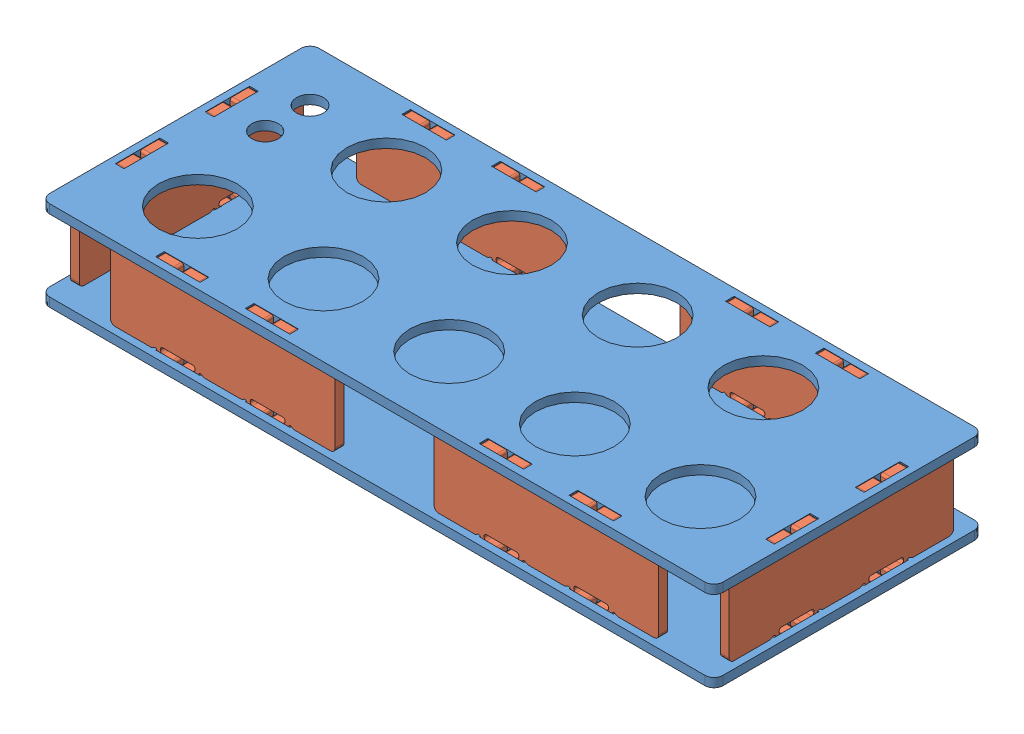
SolidWorks assembly Popn Controller v2, configuration Default. Lengths in mm.
Overall size (750 100 300).
8 component instances, 2 part files, 21 mates.
Components (placement in the parent):
- Face-1: Face [Top] at (-159.3551 406.3492 746.0654) size (750 10 300)
- Support-1: Support [Default] at (-141.3551 326.3492 471.0654) x (0 0 1) z (-1 0 0) size (250 99 10)
- Support-2: Support [Default] at (-89.6051 326.3492 728.0654) size (250 99 10)
- Support-3: Support [Default] at (-89.6051 326.3492 454.0654) size (250 99 10)
- Support-4: Support [Default] at (270.8949 326.3492 454.0654) size (250 99 10)
- Support-5: Support [Default] at (572.6449 406.3492 471.0654) x (0 0 1) z (1 0 0) size (250 99 10)
- Support-6: Support [Default] at (270.8949 326.3492 728.0654) size (250 99 10)
- Face-2: Face [Bottom] at (-159.3551 316.3492 746.0654) size (750 10 300)
Mates (geometry in assembly coordinates):
- Coincident1: coincident anti-aligned: plane of Face-1 through (-159.3551 406.3492 746.0654) normal (0 -1 0); plane of Support-6 through (270.8949 406.3492 738.0654) normal (0 1 0)
- Coincident2: coincident anti-aligned: plane of Face-1 through (370.6449 406.3492 738.0654) normal (0 0 -1); plane of Support-6 through (270.8949 326.3492 738.0654) normal (0 0 1)
- Width1: width anti-aligned: plane of Face-1 through (321.1449 406.3492 738.0654) normal (1 0 0); plane of Face-1 through (470.6449 406.3492 728.4654) normal (-1 0 0); plane of Support-6 through (270.8949 326.3492 738.0654) normal (-1 0 0); plane of Support-6 through (520.8949 326.3492 738.0654) normal (1 0 0)
- Coincident5: coincident anti-aligned: plane of Face-1 through (60.6449 406.3492 738.0654) normal (0 0 -1); plane of Support-2 through (-89.6051 326.3492 738.0654) normal (0 0 1)
- Coincident6: coincident anti-aligned: plane of Face-1 through (-159.3551 406.3492 746.0654) normal (0 -1 0); plane of Support-2 through (-89.6051 406.3492 738.0654) normal (0 1 0)
- Width2: width aligned: plane of Face-1 through (110.1449 406.3492 738.0654) normal (-1 0 0); plane of Face-1 through (-39.3551 406.3492 728.4654) normal (1 0 0); plane of Support-2 through (-89.6051 326.3492 738.0654) normal (-1 0 0); plane of Support-2 through (160.3949 326.3492 738.0654) normal (1 0 0)
- Coincident7: coincident anti-aligned: plane of Face-1 through (-151.3551 406.3492 521.3154) normal (1 0 0); plane of Support-1 through (-151.3551 326.3492 471.0654) normal (-1 0 0)
- Coincident8: coincident anti-aligned: plane of Face-1 through (-159.3551 406.3492 746.0654) normal (0 -1 0); plane of Support-1 through (-151.3551 406.3492 471.0654) normal (0 1 0)
- Width3: width anti-aligned: plane of Face-1 through (-141.7551 406.3492 521.3154) normal (0 0 1); plane of Face-1 through (-141.7551 406.3492 670.8154) normal (0 0 -1); plane of Support-1 through (-151.3551 326.3492 471.0654) normal (0 0 -1); plane of Support-1 through (-151.3551 326.3492 721.0654) normal (0 0 1)
- Coincident9: coincident anti-aligned: plane of Support-1 through (-151.3551 326.3492 471.0654) normal (-1 0 0); plane of Face-2 through (-151.3551 316.3492 521.3154) normal (1 0 0)
- Coincident10: coincident anti-aligned: plane of Support-1 through (-151.3551 326.3492 471.0654) normal (0 -1 0); plane of Face-2 through (-159.3551 326.3492 746.0654) normal (0 1 0)
- Width4: width anti-aligned: plane of Face-2 through (-141.7551 316.3492 521.3154) normal (0 0 1); plane of Face-2 through (-141.7551 316.3492 670.8154) normal (0 0 -1); plane of Support-1 through (-151.3551 326.3492 471.0654) normal (0 0 -1); plane of Support-1 through (-151.3551 326.3492 721.0654) normal (0 0 1)
- Coincident11: coincident anti-aligned: plane of Face-1 through (582.6449 406.3492 521.3154) normal (-1 0 0); plane of Support-5 through (582.6449 406.3492 471.0654) normal (1 0 0)
- Width5: width anti-aligned: plane of Face-1 through (573.0449 406.3492 521.3154) normal (0 0 1); plane of Face-1 through (573.0449 406.3492 670.8154) normal (0 0 -1); plane of Support-5 through (582.6449 406.3492 471.0654) normal (0 0 -1); plane of Support-5 through (582.6449 406.3492 721.0654) normal (0 0 1)
- Coincident13: coincident anti-aligned: plane of Face-1 through (-159.3551 406.3492 746.0654) normal (0 -1 0); plane of Support-5 through (582.6449 406.3492 471.0654) normal (0 1 0)
- Coincident14: coincident anti-aligned: plane of Face-1 through (470.6449 406.3492 454.0654) normal (0 0 1); plane of Support-4 through (270.8949 326.3492 454.0654) normal (0 0 -1)
- Coincident15: coincident anti-aligned: plane of Face-1 through (-159.3551 406.3492 746.0654) normal (0 -1 0); plane of Support-4 through (270.8949 406.3492 464.0654) normal (0 1 0)
- Width6: width anti-aligned: plane of Face-1 through (470.6449 406.3492 463.6654) normal (-1 0 0); plane of Face-1 through (321.1449 406.3492 454.0654) normal (1 0 0); plane of Support-4 through (520.8949 326.3492 464.0654) normal (1 0 0); plane of Support-4 through (270.8949 326.3492 464.0654) normal (-1 0 0)
- Coincident16: coincident anti-aligned: plane of Face-1 through (-39.3551 406.3492 454.0654) normal (0 0 1); plane of Support-3 through (-89.6051 326.3492 454.0654) normal (0 0 -1)
- Coincident17: coincident anti-aligned: plane of Face-1 through (-159.3551 406.3492 746.0654) normal (0 -1 0); plane of Support-3 through (-89.6051 406.3492 464.0654) normal (0 1 0)
- Width7: width anti-aligned: plane of Face-1 through (-39.3551 406.3492 463.6654) normal (1 0 0); plane of Face-1 through (110.1449 406.3492 454.0654) normal (-1 0 0); plane of Support-3 through (-89.6051 326.3492 464.0654) normal (-1 0 0); plane of Support-3 through (160.3949 326.3492 464.0654) normal (1 0 0)
